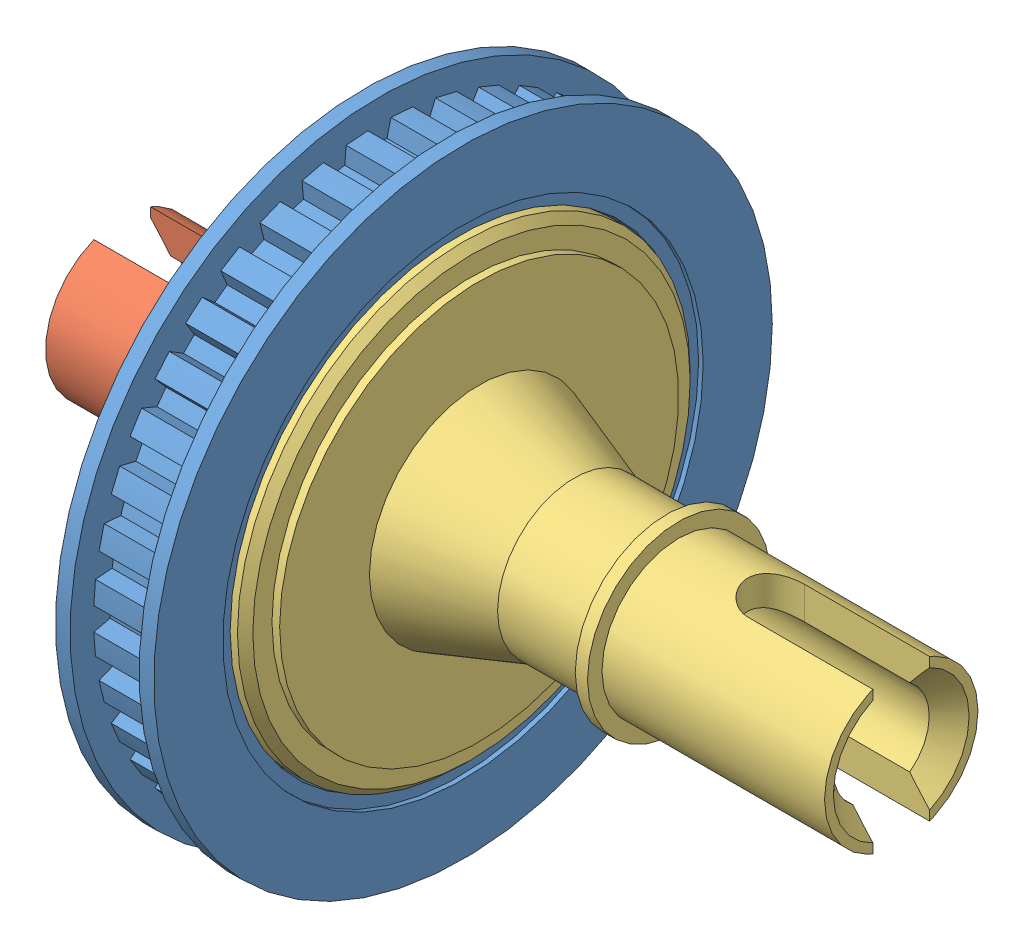
SolidWorks assembly Kugel-Diff Hobbyking Mission-D, configuration Standard. Lengths in mm.
Overall size (50.75 40.3 40.3).
5 component instances, 4 part files, 15 mates.
Components (placement in the parent):
- Kugel-Diff Hobbyking Mission-D Riemenrad-1: Kugel-Diff Hobbyking Mission-D Riemenrad [Standard] at origin size (6.4 40.3 40.3)
- Kugel-Diff Hobbyking Mission-D Achse1-1: Kugel-Diff Hobbyking Mission-D Achse1 [Standard] at (-2.25 0 0) x (0 0 1) z (-1 0 0) size (29.5 29.5 22)
- Kugel-Diff Hobbyking Mission-D Achse2-1: Kugel-Diff Hobbyking Mission-D Achse2 [Standard] at (2.25 0 0) x (0 0 -1) z (1 0 0) size (29.5 29.5 30)
- Kugel-Diff Hobbyking Mission-D Laufscheibe-2: Kugel-Diff Hobbyking Mission-D Laufscheibe [Standard] at (1.95 0 0) x (0 0 -1) z (1 0 0) size (25 25 0.6)
- Kugel-Diff Hobbyking Mission-D Laufscheibe-3: Kugel-Diff Hobbyking Mission-D Laufscheibe [Standard] at (-1.95 0 0) x (0 0 1) z (-1 0 0) size (25 25 0.6)
Mates (geometry in assembly coordinates):
- Deckungsgleich1: coincident aligned: plane of Kugel-Diff Hobbyking Mission-D Riemenrad-1 through (0 0 0) normal (0 1 0); plane of assembly through (0 0 0) normal (0 1 0)
- Deckungsgleich2: coincident aligned: plane of Kugel-Diff Hobbyking Mission-D Riemenrad-1 through (0 0 0) normal (1 0 0); plane of assembly through (0 0 0) normal (1 0 0)
- Deckungsgleich3: coincident aligned: plane of Kugel-Diff Hobbyking Mission-D Riemenrad-1 through (0 0 0) normal (0 0 1); plane of assembly through (0 0 0) normal (0 0 1)
- Deckungsgleich4: coincident anti-aligned: plane of Kugel-Diff Hobbyking Mission-D Achse1-1 through (-2.25 9.5 0) normal (1 0 0); plane of Kugel-Diff Hobbyking Mission-D Laufscheibe-3 through (-2.25 0 0) normal (-1 0 0)
- Konzentrisch1: concentric aligned: cylinder of Kugel-Diff Hobbyking Mission-D Achse1-1 through (8.3564 0 0) axis (1 0 0) radius 9.5; cylinder of Kugel-Diff Hobbyking Mission-D Laufscheibe-3 through (-2.25 0 0) axis (1 0 0) radius 9.5
- Deckungsgleich5: coincident: plane of Kugel-Diff Hobbyking Mission-D Achse1-1 through (-44.3865 8.5 10) normal (0 1 0); plane of Kugel-Diff Hobbyking Mission-D Laufscheibe-3 through (-2.25 8.5 -4.2426) normal (0 -1 0)
- Deckungsgleich6: coincident anti-aligned: plane of Kugel-Diff Hobbyking Mission-D Achse2-1 through (2.25 9.5 0) normal (-1 0 0); plane of Kugel-Diff Hobbyking Mission-D Laufscheibe-2 through (2.25 0 0) normal (1 0 0)
- Konzentrisch2: concentric aligned: cylinder of Kugel-Diff Hobbyking Mission-D Achse2-1 through (-8.3564 0 0) axis (-1 0 0) radius 9.5; cylinder of Kugel-Diff Hobbyking Mission-D Laufscheibe-2 through (2.25 0 0) axis (-1 0 0) radius 9.5
- Deckungsgleich7: coincident anti-aligned: plane of Kugel-Diff Hobbyking Mission-D Achse2-1 through (44.3865 -8.5 -10) normal (0 -1 0); plane of Kugel-Diff Hobbyking Mission-D Laufscheibe-2 through (2.25 -8.5 -4.2426) normal (0 1 0)
- Konzentrisch3: concentric anti-aligned: cylinder of Kugel-Diff Hobbyking Mission-D Riemenrad-1 through (-3.7535 0 0) axis (1 0 0) radius 6; cylinder of Kugel-Diff Hobbyking Mission-D Achse2-1 through (-8.3564 0 0) axis (-1 0 0) radius 3.9
- Konzentrisch4: concentric aligned: cylinder of Kugel-Diff Hobbyking Mission-D Riemenrad-1 through (-3.7535 0 0) axis (1 0 0) radius 6; cylinder of Kugel-Diff Hobbyking Mission-D Achse1-1 through (8.3564 0 0) axis (1 0 0) radius 2.5
- Deckungsgleich8: coincident aligned: plane of Kugel-Diff Hobbyking Mission-D Achse1-1; plane of assembly through (0 0 0) normal (0 1 0)
- Deckungsgleich9: coincident aligned: plane of Kugel-Diff Hobbyking Mission-D Achse2-1; plane of assembly through (0 0 0) normal (0 1 0)
- Abstand1: distance = 1.65 mm anti-aligned: plane of Kugel-Diff Hobbyking Mission-D Laufscheibe-2 through (1.65 0 0) normal (-1 0 0); plane of assembly through (0 0 0) normal (1 0 0)
- Symmetrisch1: symmetric aligned: plane of Kugel-Diff Hobbyking Mission-D Laufscheibe-2 through (1.65 0 0) normal (-1 0 0); plane of Kugel-Diff Hobbyking Mission-D Laufscheibe-3 through (-1.65 0 0) normal (1 0 0); plane of assembly through (0 0 0) normal (1 0 0)
